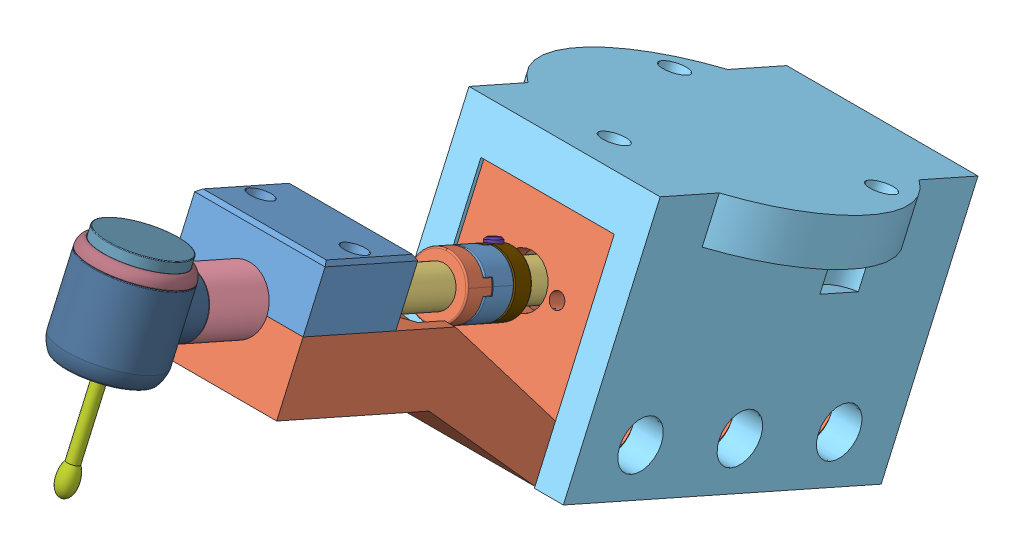
SolidWorks assembly 組合件1, configuration 預設. Lengths in mm.
Overall size (40.1 69.78 119.29).
30 component instances, 23 part files, 14 mates.
Components (placement in the parent):
- main_handpiece-1: main_handpiece [預設] at (-2.3613 121.0882 171.1883) x (0 -0.405184 -0.914235) z (1 0 0) size (91 27 18)
  - cover-1: cover [預設] at (-60 18.5 0) size (14 8 18)
  - handpiece-1: handpiece [預設] at origin size (91 27 18)
- Drill Assembly-1: Drill Assembly [Default] at (-5.4046 158.3058 242.2653) x (0 -0.914235 0.405184) z (-1 0 0) size (27.75 14.83 12.65)
  - Chuck-2: Chuck [Default] at (-14.7562 4.439 -3.0244) x (1 0 0) z (0 -1 0) size (12 3 3)
  - Spindle-1: Spindle [Default] at (-18.2562 4.439 -3.0244) x (1 0 0) z (0 0.494634 0.869101) size (12 4.7 4.61)
  - Rotor-1: Rotor [Default] at (-11.7562 4.439 -3.0244) size (4.02 10.24 10.24)
  - Chuck slider-1: Chuck slider [Default] at (-14.6486 4.439 -3.0244) x (1 0 0) z (0 -0.313569 -0.949565) size (2 2.2 2.2)
  - Burr-2: Burr [Default] at (-10.7562 4.439 -3.0244) size (22.04 2.98 2.98)
  - Ball bearings-1: Ball bearings [Default] at (-6.5062 4.439 -3.0244) size (2.5 7 7)
  - Ball bearings-2: Ball bearings [Default] at (-13.0062 4.439 -3.0244) x (-1 0 0) z (0 0.924225 0.381849) size (2.5 7 7)
  - O-ring-1: O-ring [Default] at (-6.2562 4.439 -3.0244) size (1 9 9)
  - O-ring-2: O-ring [Default] at (-13.2562 4.439 -3.0244) x (-1 0 0) z (0 -0.924225 -0.381849) size (1 9 9)
  - Head-1: Head [Default] at (-2.7562 4.439 -3.0244) size (11.14 14.83 12.65)
  - Water cap-1: Water cap [Default] at (-2.7562 4.439 -3.0244) size (2 10.65 10.65)
  - Water lock-1: Water lock [Default] at (-2.7562 4.439 -3.0244) size (3 10.73 10.65)
  - Back-cap-1: Back-cap [Default] at (-13.7562 4.439 -3.0244) size (2.98 12.64 12.64)
  - Back-cap tab-1: Back-cap tab [Default] at (-16.0062 4.439 -3.0244) x (1 0 0) z (0 0.076281 0.997086) size (3.25 11.57 11.57)
  - Sacraficial anode-1: Sacraficial anode [Default] at (-14.7562 4.439 -3.0244) size (0.5 9.77 9.77)
  - Back-cap spring-2: Back-cap spring [Default] at (-15.0656 4.4342 -2.9768) size (1.21 11.14 9.66)
- CPO7_9_3_3-1: CPO7_9_3_3 [Default] at (-2.3613 149.3365 199.1398) x (0 -0.405184 -0.914235) z (-0.932993 -0.329027 0.145823) size (9.8 9.45 9.45)
  - CPO7_9_3_3_3-1: CPO7_9_3_3_3 [Default] at (1.25 0 1.5) x (0 0 -1) z (-1 0 0) size (3 2 2)
  - CPO7_9_3_3_3-2: CPO7_9_3_3_3 [Default] at (8.55 -1.5 0) x (0 1 0) z (1 0 0) size (3 2 2)
  - CPO7_9_3_3_6-1: CPO7_9_3_3_6 [Default] at (9.8 0 0) x (-1 0 0) z (0 -1 0) size (3.9 9.45 9.45)
  - CPO7_9_3_3_8-1: CPO7_9_3_3_8 [Default] at (4.8 0 0) size (4.4 7.9 7.9)
  - CPO7_9_3_3_10-1: CPO7_9_3_3_10 [Default] at origin size (3.9 9.45 9.45)
- axis-1: axis [預設] at (-2.3613 155.4142 212.8534) x (0.912586 0.373817 -0.165674) z (0 -0.405184 -0.914235) size (5 5 30)
- axis-2: axis [預設] at (-2.3613 139.2879 176.4668) x (0.989989 0.129039 -0.05719) z (0 0.405184 0.914235) size (5 5 30)
- tool part-1: tool part [預設] at (-2.3613 163.3153 230.6809) x (0.999816 -0.017537 0.007772) z (0 0.405184 0.914235) size (8 8 9)
- main_adapter_finetune-2: main_adapter_finetune [預設] at (-15.7613 117.7056 172.6875) x (1 0 0) z (0 0.405184 0.914235) size (40.1 33 48)
Mates (geometry in assembly coordinates):
- 重合/共線/共點1: coincident: plane of CPO7_9_3_3-1/CPO7_9_3_3_6-1 through (-2.3613 145.3657 190.1803) normal (0 -0.405184 -0.914235); plane of axis-2 through (-2.3613 145.3657 190.1803) normal (0 0.405184 0.914235)
- 重合/共線/共點2: coincident: plane of main_handpiece-1/cover-1 through (6.6387 168.8059 223.3254) normal (0 0.405184 0.914235); plane of tool part-1 through (-2.3613 161.492 226.5669) normal (0 -0.405184 -0.914235)
- 重合/共線/共點3: coincident: plane of Drill Assembly-1/Head-1 through (-2.3613 165.1386 234.795) normal (0 -0.405184 -0.914235); plane of tool part-1 through (-2.3613 165.1386 234.795) normal (0 0.405184 0.914235)
- 重合/共線/共點4: coincident: plane of axis-1 through (-2.3613 161.492 226.5669) normal (0 0.405184 0.914235); plane of tool part-1 through (-2.3613 161.492 226.5669) normal (0 -0.405184 -0.914235)
- 重合/共線/共點5: coincident: plane of main_handpiece-1/handpiece-1 through (-2.3613 142.5728 161.6665) normal (0 0.914235 -0.405184); plane of main_adapter_finetune-2 through (6.6387 152.2972 183.6081) normal (0 -0.914235 0.405184)
- 重合/共線/共點6: coincident: plane of main_handpiece-1/handpiece-1 through (6.6387 114.5636 147.8285) normal (0 -0.405184 -0.914235); plane of main_adapter_finetune-2 through (-15.7613 107.9811 150.7458) normal (0 -0.405184 -0.914235)
- 平行1: parallel: plane of main_handpiece-1/cover-1 through (-2.3613 165.9696 216.9258) normal (0 0.914235 -0.405184); plane of Drill Assembly-1/Back-cap tab-1 through (-2.3801 175.1949 239.6355) normal (0 0.914235 -0.405184)
- 重合/共線/共點7: coincident: plane of main_handpiece-1/handpiece-1 through (6.6387 134.0125 191.7118) normal (1 0 0); plane of main_adapter_finetune-2 through (6.6387 127.43 194.6291) normal (-1 0 0)
- 同軸心1: concentric: cylinder of axis-1 through (-2.3613 149.3365 199.1398) axis (0 0.405184 0.914235) radius 2.5; cylinder of tool part-1 through (-2.3613 165.1386 234.795) axis (0 -0.405184 -0.914235) radius 4
- 同軸心2: concentric: cylinder of main_handpiece-1/handpiece-1 through (-2.3613 160.6816 224.7384) axis (0 0.405184 0.914235) radius 3.5; cylinder of Drill Assembly-1/Head-1 through (-2.3613 165.1386 234.795) axis (0 0.405184 0.914235) radius 3
- 同軸心3: concentric: cylinder of CPO7_9_3_3-1/CPO7_9_3_3_10-1 through (-2.3613 147.7562 195.5743) axis (0 -0.405184 -0.914235) radius 1.5; cylinder of axis-1 through (-2.3613 149.3365 199.1398) axis (0 0.405184 0.914235) radius 2.5
- 同軸心4: concentric: cylinder of axis-1 through (-2.3613 149.3365 199.1398) axis (0 0.405184 0.914235) radius 2.5; cylinder of axis-2 through (-2.3613 145.3657 190.1803) axis (0 -0.405184 -0.914235) radius 2.5
- 同軸心5: concentric: cylinder of main_handpiece-1/handpiece-1 through (-2.3613 160.6816 224.7384) axis (0 0.405184 0.914235) radius 3.5; cylinder of tool part-1 through (-2.3613 165.1386 234.795) axis (0 -0.405184 -0.914235) radius 4
- 重合/共線/共點8: coincident: plane of CPO7_9_3_3-1/CPO7_9_3_3_10-1 through (-2.3613 149.3365 199.1398) normal (0 0.405184 0.914235); plane of axis-1 through (-2.3613 149.3365 199.1398) normal (0 -0.405184 -0.914235)
